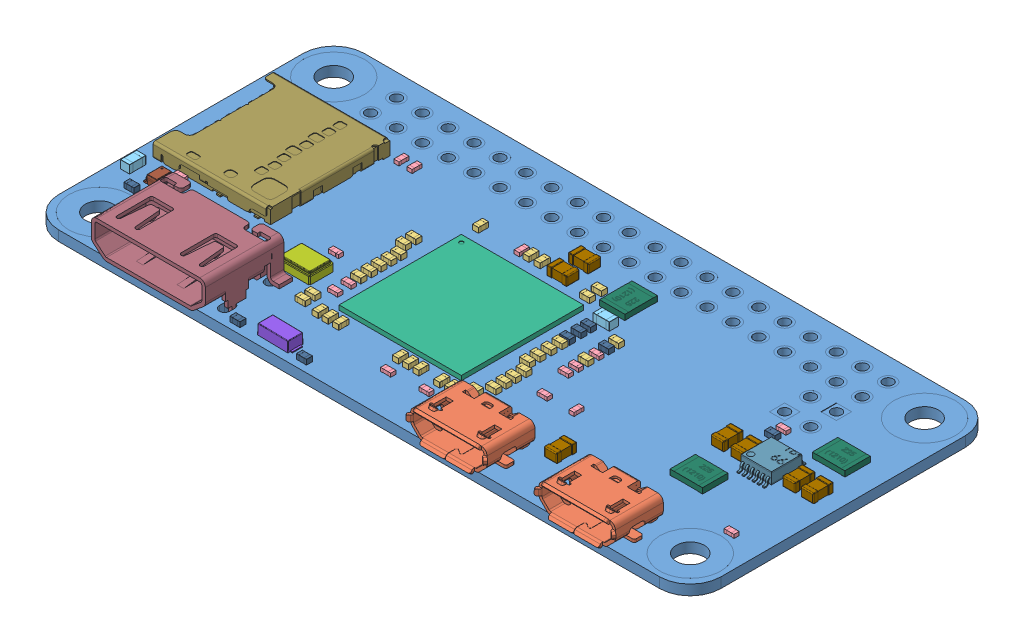
SolidWorks assembly RapberryPiZero, configuration Default. Lengths in mm.
Overall size (65 4.45 30.6).
81 component instances, 15 part files, 174 mates.
Components (placement in the parent):
- Raspberry_pizero_PCB-1: Raspberry_pizero_PCB [Default] at (-51.2564 20.0966 13.0542) size (65 1 30)
- Micro USB_input_female (short)-SMT-1: Micro USB_input_female (short)-SMT [Default] at (-42.3564 22.3216 25.8042) size (7.98 2.94 5.43)
- Micro USB_input_female (short)-SMT-2: Micro USB_input_female (short)-SMT [Default] at (-29.7564 22.3216 25.8042) size (7.98 2.94 5.43)
- 0204 - Capacitor-1: 0204 - Capacitor [Default] at (-62.4121 21.3466 11.2398) size (1 0.5 0.6)
- 0204 - Capacitor-2: 0204 - Capacitor [Default] at (-62.4121 21.3466 12.2528) size (1 0.5 0.6)
- 0204 - Capacitor-3: 0204 - Capacitor [Default] at (-61.8122 21.3466 13.3136) size (1 0.5 0.6)
- 0204 - Capacitor-4: 0204 - Capacitor [Default] at (-61.8122 21.3466 14.2646) size (1 0.5 0.6)
- 0204 - Capacitor-5: 0204 - Capacitor [Default] at (-61.8122 21.3466 15.241) size (1 0.5 0.6)
- 0204 - Capacitor-6: 0204 - Capacitor [Default] at (-61.8122 21.3466 16.2144) size (1 0.5 0.6)
- 0204 - Capacitor-7: 0204 - Capacitor [Default] at (-61.8122 21.3466 17.2416) size (1 0.5 0.6)
- 0204 - Capacitor-8: 0204 - Capacitor [Default] at (-62.5919 21.3466 20.9695) size (1 0.5 0.6)
- 0204 - Capacitor-9: 0204 - Capacitor [Default] at (-62.5919 21.3466 21.919) size (1 0.5 0.6)
- 0204 - Capacitor-10: 0204 - Capacitor [Default] at (-60.4584 21.3466 22.3712) x (0 0 1) z (-1 0 0) size (1 0.5 0.6)
- 0204 - Capacitor-11: 0204 - Capacitor [Default] at (-60.0807 21.3466 22.3712) x (0 0 -1) z (1 0 0) size (1 0.5 0.6)
- 0204 - Capacitor-12: 0204 - Capacitor [Default] at (-59.0466 21.3466 22.3712) x (0 0 -1) z (1 0 0) size (1 0.5 0.6)
- 0204 - Capacitor-13: 0204 - Capacitor [Default] at (-52.6496 21.3466 22.316) x (0 0 1) z (-1 0 0) size (1 0.5 0.6)
- 0204 - Capacitor-14: 0204 - Capacitor [Default] at (-52.25 21.3466 22.316) x (0 0 -1) z (1 0 0) size (1 0.5 0.6)
- 0204 - Capacitor-15: 0204 - Capacitor [Default] at (-51.2398 21.3466 22.316) x (0 0 -1) z (1 0 0) size (1 0.5 0.6)
- 0204 - Capacitor-16: 0204 - Capacitor [Default] at (-49.1841 21.3466 22.316) x (0 0 -1) z (1 0 0) size (1 0.5 0.6)
- 0204 - Capacitor-17: 0204 - Capacitor [Default] at (-48.1448 21.3466 22.316) x (0 0 -1) z (1 0 0) size (1 0.5 0.6)
- 0204 - Capacitor-18: 0204 - Capacitor [Default] at (-46.475 21.3466 21.113) size (1 0.5 0.6)
- 0204 - Capacitor-19: 0204 - Capacitor [Default] at (-45.7322 21.3466 20.0663) size (1 0.5 0.6)
- 0204 - Capacitor-20: 0204 - Capacitor [Default] at (-45.7322 21.3466 19.0675) size (1 0.5 0.6)
- 0204 - Capacitor-21: 0204 - Capacitor [Default] at (-45.7322 21.3466 18.1249) size (1 0.5 0.6)
- 0204 - Capacitor-22: 0204 - Capacitor [Default] at (-45.7322 21.3466 17.1095) size (1 0.5 0.6)
- 0204 - Capacitor-23: 0204 - Capacitor [Default] at (-46.3457 21.3466 16.1412) size (1 0.5 0.6)
- 0204 - Capacitor-24: 0204 - Capacitor [Default] at (-46.3457 21.3466 15.1229) size (1 0.5 0.6)
- 0204 - Capacitor-25: 0204 - Capacitor [Default] at (-46.3457 21.3466 14.0197) size (1 0.5 0.6)
- 0204 - Capacitor-26: 0204 - Capacitor [Default] at (-46.3457 21.3466 12.9589) size (1 0.5 0.6)
- 0204 - Capacitor-27: 0204 - Capacitor [Default] at (-43.6156 21.3466 13.1418) size (1 0.5 0.6)
- 0204 - Capacitor-28: 0204 - Capacitor [Default] at (-43.6156 21.3466 10.1424) size (1 0.5 0.6)
- 0204 - Capacitor-29: 0204 - Capacitor [Default] at (-48.9117 21.3466 7.6917) size (1 0.5 0.6)
- 0204 - Capacitor-30: 0204 - Capacitor [Default] at (-55.4926 21.3466 7.2526) x (0 0 -1) z (1 0 0) size (1 0.5 0.6)
- 0204 - Capacitor-31: 0204 - Capacitor [Default] at (-53.7932 21.3466 7.2526) x (0 0 1) z (-1 0 0) size (1 0.5 0.6)
- 0204 - Capacitor-32: 0204 - Capacitor [Default] at (-59.8477 21.3466 7.2526) x (0 0 1) z (-1 0 0) size (1 0.5 0.6)
- 0204- Resistor-15: 0204- Resistor [Default] at (-43.6109 21.4522 15.4193) x (-1 0 0) z (0 -1 0) size (0.99 0.51 0.36)
- 0204- Resistor-14: 0204- Resistor [Default] at (-43.6109 21.4522 14.4127) x (-1 0 0) z (0 -1 0) size (0.99 0.51 0.36)
- 0204- Resistor-13: 0204- Resistor [Default] at (-43.6109 21.4522 12.4047) x (-1 0 0) z (0 -1 0) size (0.99 0.51 0.36)
- 0204- Resistor-4: 0204- Resistor [Default] at (-42.6936 21.4522 18.4076) x (-1 0 0) z (0 -1 0) size (0.99 0.51 0.36)
- 0204- Resistor-5: 0204- Resistor [Default] at (-39.831 21.4522 18.1462) x (0 0 1) z (0 -1 0) size (0.99 0.51 0.36)
- 0204- Resistor-7: 0204- Resistor [Default] at (-61.8169 21.4522 19.8533) x (-1 0 0) z (0 -1 0) size (0.99 0.51 0.36)
- 0204- Resistor-8: 0204- Resistor [Default] at (-61.8169 21.4522 18.5178) x (-1 0 0) z (0 -1 0) size (0.99 0.51 0.36)
- 0204- Resistor-9: 0204- Resistor [Default] at (-79.148 21.4522 17.7279) x (-1 0 0) z (0 -1 0) size (0.99 0.51 0.36)
- 0204- Resistor-10: 0204- Resistor [Default] at (-56.0985 21.4522 7.2479) x (0 0 -1) z (0 -1 0) size (0.99 0.51 0.36)
- 0204- Resistor-11: 0204- Resistor [Default] at (-28.0827 21.4522 9.5819) x (-1 0 0) z (0 -1 0) size (0.99 0.51 0.36)
- 0204- Resistor-12: 0204- Resistor [Default] at (-21.8613 21.4522 20.9026) x (-1 0 0) z (0 -1 0) size (0.99 0.51 0.36)
- CAP-0306-1: CAP-0306 [Default] at (-45.8903 21.4966 8.7634) size (1.6 0.8 0.9)
- CAP-0306-2: CAP-0306 [Default] at (-82.0031 21.4966 19.0464) x (0 0 1) z (-1 0 0) size (1.6 0.8 0.9)
- Raspberry_pizero_BCM2835 with VC4-2: Raspberry_pizero_BCM2835 with VC4 [Default] at (-54.1608 21.5466 15.1238) x (1 0 0) z (0 0 -1) size (12 0.65 12)
- Crystal 3.4x2.4mm-1: Crystal 3.4x2.4mm [Default] at (-65.3089 21.0966 19.2633) size (3.2 1 2.4)
- 0204- Resistor-16: 0204- Resistor [Default] at (-68.4329 21.4522 5.4384) x (0 0 1) z (0 -1 0) size (0.99 0.51 0.36)
- 0204- Resistor-17: 0204- Resistor [Default] at (-69.7255 21.4522 5.4384) x (0 0 1) z (0 -1 0) size (0.99 0.51 0.36)
- 0204- Resistor-18: 0204- Resistor [Default] at (-65.0626 21.4522 16.5355) x (1 0 0) z (0 -1 0) size (0.99 0.51 0.36)
- 32,768 Khz Crystal-1: 32,768 Khz Crystal [Default] at (-60.5154 21.1428 26.5473) x (0.999848 -0.017452 0) z (0 0 1) size (3.4 1.03 1.5)
- 0805- Capacitor-1: 0805- Capacitor [Default] at (-51.9496 21.9966 5.2384) x (1 0 0) z (0 -1 0) size (2 1.25 0.9)
- 0805- Capacitor-2: 0805- Capacitor [Default] at (-51.9496 21.9966 7.3589) x (1 0 0) z (0 -1 0) size (2 1.25 0.9)
- 0805- Capacitor-3: 0805- Capacitor [Default] at (-37.009 21.9966 22.5384) x (0 0 -1) z (0 -1 0) size (2 1.25 0.9)
- 0805- Capacitor-4: 0805- Capacitor [Default] at (-29.8247 21.9966 13.3538) x (0 0 1) z (0 -1 0) size (2 1.25 0.9)
- 0805- Capacitor-5: 0805- Capacitor [Default] at (-27.9052 21.9966 13.3538) x (0 0 -1) z (0 -1 0) size (2 1.25 0.9)
- 0805- Capacitor-6: 0805- Capacitor [Default] at (-22.8003 21.9966 13.3538) x (0 0 -1) z (0 -1 0) size (2 1.25 0.9)
- 0805- Capacitor-7: 0805- Capacitor [Default] at (-20.9924 21.9966 13.3538) x (0 0 -1) z (0 -1 0) size (2 1.25 0.9)
- 0204- Resistor-19: 0204- Resistor [Default] at (-48.8769 21.4522 23.8207) x (1 0 0) z (0 -1 0) size (0.99 0.51 0.36)
- 0204- Resistor-20: 0204- Resistor [Default] at (-52.4165 21.4522 24.0419) x (1 0 0) z (0 -1 0) size (0.99 0.51 0.36)
- 0204 - Capacitor-33: 0204 - Capacitor [Default] at (-47.1199 21.3466 23.926) x (0 0 1) z (-1 0 0) size (1 0.5 0.6)
- 0204 - Capacitor Brown-34: 0204 - Capacitor Brown [Default] at (-57.5817 21.3466 26.803) size (1 0.5 0.6)
- 0204 - Capacitor Brown-35: 0204 - Capacitor Brown [Default] at (-64.0312 21.3466 26.8794) size (1 0.5 0.6)
- 0204 - Capacitor Brown-36: 0204 - Capacitor Brown [Default] at (-46.3457 21.3466 12.214) size (1 0.5 0.6)
- 0204 - Capacitor Brown-37: 0204 - Capacitor Brown [Default] at (-46.3457 21.3466 11.0963) size (1 0.5 0.6)
- 0204 - Capacitor Brown-38: 0204 - Capacitor Brown [Default] at (-46.3457 21.3466 10.1566) size (1 0.5 0.6)
- 0204 - Capacitor Brown-39: 0204 - Capacitor Brown [Default] at (-43.6156 21.3466 11.1151) size (1 0.5 0.6)
- 0204 - Capacitor Brown-40: 0204 - Capacitor Brown [Default] at (-28.0874 21.3466 10.3236) size (1 0.5 0.6)
- 0204 - Capacitor Brown-41: 0204 - Capacitor Brown [Default] at (-80.6197 21.3466 20.6997) size (1 0.5 0.6)
- 0204- Resistor-21: 0204- Resistor [Default] at (-78.9105 21.4522 21.1554) x (1 0 0) z (0 -1 0) size (0.99 0.51 0.36)
- 6-Pin SOT-1: 6-Pin SOT [Default] at (-79.714 21.0966 19.2138) x (0 0 1) z (0 1 0) size (1.5 1.84 0.95)
- micro sd molex-1: micro sd molex [Default] at (-74.7768 21.6766 -33.0961) x (0 0 1) z (0 1 0) size (11.95 11.4 1.45)
- hdmi type C-1: hdmi type C [Default] at (-71.3564 22.9466 28.6542) size (12.9 4.05 7.7)
- Voltage Regulator 3x3mm 12-Pin-1: Voltage Regulator 3x3mm 12-Pin [Default] at (-23.6842 21.0966 12.6105) x (1 0 0) z (0 1 0) size (3 4.1 1.2)
- 1210 inductor-1: 1210 inductor [Default] at (-46.4963 21.0916 6.3909) x (0 0 1) z (0 1 0) size (3.26 2.86 0.75)
- 1210 inductor-2: 1210 inductor [Default] at (-22.7405 21.0916 9.2394) x (1 0 0) z (0 1 0) size (3.26 2.86 0.75)
- 1210 inductor-3: 1210 inductor [Default] at (-28.2854 21.0916 17.6682) x (1 0 0) z (0 1 0) size (3.26 2.86 0.75)
- 0204 - Capacitor-34: 0204 - Capacitor [Default] at (-48.9117 21.3466 6.5273) size (1 0.5 0.6)
Mates (geometry in assembly coordinates):
- Coincident1: coincident anti-aligned: plane of Raspberry_pizero_PCB-1 through (-80.7564 21.0966 1.0542) normal (0 1 0); plane of Micro USB_input_female (short)-SMT-1 through (-46.4124 21.0966 24.1966) normal (0 -1 0)
- Coincident2: coincident anti-aligned: plane of Raspberry_pizero_PCB-1 through (-80.7564 21.0966 1.0542) normal (0 1 0); plane of Micro USB_input_female (short)-SMT-2 through (-33.8124 21.0966 24.1966) normal (0 -1 0)
- Coincident3: coincident aligned: plane of 0204 - Capacitor-13 through (-52.9516 21.5916 22.316) normal (0 1 0); plane of 0204 - Capacitor-14 through (-51.948 21.5916 22.316) normal (0 1 0)
- Coincident4: coincident aligned: plane of 0204 - Capacitor-14 through (-51.948 21.5916 22.316) normal (0 1 0); plane of 0204 - Capacitor-15 through (-50.9378 21.5916 22.316) normal (0 1 0)
- Coincident5: coincident aligned: plane of 0204 - Capacitor-15 through (-50.9378 21.5916 22.316) normal (0 1 0); plane of 0204 - Capacitor-16 through (-48.8821 21.5916 22.316) normal (0 1 0)
- Coincident6: coincident aligned: plane of 0204 - Capacitor-16 through (-48.8821 21.5916 22.316) normal (0 1 0); plane of 0204 - Capacitor-17 through (-47.8428 21.5916 22.316) normal (0 1 0)
- Coincident7: coincident aligned: plane of 0204 - Capacitor-17 through (-47.8428 21.5916 22.316) normal (0 1 0); plane of 0204 - Capacitor-18 through (-46.475 21.5916 21.415) normal (0 1 0)
- Coincident8: coincident aligned: plane of 0204 - Capacitor-18 through (-46.475 21.5916 21.415) normal (0 1 0); plane of 0204 - Capacitor-19 through (-45.7322 21.5916 20.3683) normal (0 1 0)
- Coincident9: coincident aligned: plane of 0204 - Capacitor-19 through (-45.7322 21.5916 20.3683) normal (0 1 0); plane of 0204 - Capacitor-20 through (-45.7322 21.5916 19.3695) normal (0 1 0)
- Coincident10: coincident aligned: plane of 0204 - Capacitor-20 through (-45.7322 21.5916 19.3695) normal (0 1 0); plane of 0204 - Capacitor-21 through (-45.7322 21.5916 18.4269) normal (0 1 0)
- Coincident11: coincident aligned: plane of 0204 - Capacitor-21 through (-45.7322 21.5916 18.4269) normal (0 1 0); plane of 0204 - Capacitor-22 through (-45.7322 21.5916 17.4115) normal (0 1 0)
- Coincident12: coincident aligned: plane of 0204 - Capacitor-22 through (-45.7322 21.5916 17.4115) normal (0 1 0); plane of 0204 - Capacitor-23 through (-46.3457 21.5916 16.4432) normal (0 1 0)
- Coincident13: coincident aligned: plane of 0204 - Capacitor-23 through (-46.3457 21.5916 16.4432) normal (0 1 0); plane of 0204 - Capacitor-24 through (-46.3457 21.5916 15.4249) normal (0 1 0)
- Coincident14: coincident aligned: plane of 0204 - Capacitor-24 through (-46.3457 21.5916 15.4249) normal (0 1 0); plane of 0204 - Capacitor-25 through (-46.3457 21.5916 14.3217) normal (0 1 0)
- Coincident15: coincident aligned: plane of 0204 - Capacitor-25 through (-46.3457 21.5916 14.3217) normal (0 1 0); plane of 0204 - Capacitor-26 through (-46.3457 21.5916 13.2609) normal (0 1 0)
- Coincident16: coincident aligned: plane of 0204 - Capacitor-26 through (-46.3457 21.5916 13.2609) normal (0 1 0); plane of 0204 - Capacitor-27 through (-43.6156 21.5916 13.4438) normal (0 1 0)
- Coincident17: coincident aligned: plane of 0204 - Capacitor-27 through (-43.6156 21.5916 13.4438) normal (0 1 0); plane of 0204 - Capacitor-28 through (-43.6156 21.5916 10.4444) normal (0 1 0)
- Coincident18: coincident aligned: plane of 0204 - Capacitor-28 through (-43.6156 21.5916 10.4444) normal (0 1 0); plane of 0204 - Capacitor-29 through (-48.9117 21.5916 7.9937) normal (0 1 0)
- Coincident19: coincident aligned: plane of 0204 - Capacitor-29 through (-48.9117 21.5916 7.9937) normal (0 1 0); plane of 0204 - Capacitor-31 through (-54.0952 21.5916 7.2526) normal (0 1 0)
- Coincident20: coincident aligned: plane of 0204 - Capacitor-30 through (-55.1906 21.5916 7.2526) normal (0 1 0); plane of 0204 - Capacitor-31 through (-54.0952 21.5916 7.2526) normal (0 1 0)
- Coincident21: coincident aligned: plane of 0204 - Capacitor-30 through (-55.1906 21.5916 7.2526) normal (0 1 0); plane of 0204 - Capacitor-32 through (-60.1497 21.5916 7.2526) normal (0 1 0)
- Coincident22: coincident aligned: plane of 0204 - Capacitor-1 through (-62.4121 21.5916 11.5418) normal (0 1 0); plane of 0204 - Capacitor-32 through (-60.1497 21.5916 7.2526) normal (0 1 0)
- Coincident23: coincident aligned: plane of 0204 - Capacitor-1 through (-62.4121 21.5916 11.5418) normal (0 1 0); plane of 0204 - Capacitor-2 through (-62.4121 21.5916 12.5548) normal (0 1 0)
- Coincident24: coincident aligned: plane of 0204 - Capacitor-2 through (-62.4121 21.5916 12.5548) normal (0 1 0); plane of 0204 - Capacitor-3 through (-61.8122 21.5916 13.6156) normal (0 1 0)
- Coincident25: coincident aligned: plane of 0204 - Capacitor-3 through (-61.8122 21.5916 13.6156) normal (0 1 0); plane of 0204 - Capacitor-4 through (-61.8122 21.5916 14.5666) normal (0 1 0)
- Coincident26: coincident aligned: plane of 0204 - Capacitor-4 through (-61.8122 21.5916 14.5666) normal (0 1 0); plane of 0204 - Capacitor-5 through (-61.8122 21.5916 15.543) normal (0 1 0)
- Coincident27: coincident aligned: plane of 0204 - Capacitor-5 through (-61.8122 21.5916 15.543) normal (0 1 0); plane of 0204 - Capacitor-6 through (-61.8122 21.5916 16.5164) normal (0 1 0)
- Coincident28: coincident aligned: plane of 0204 - Capacitor-6 through (-61.8122 21.5916 16.5164) normal (0 1 0); plane of 0204 - Capacitor-7 through (-61.8122 21.5916 17.5436) normal (0 1 0)
- Coincident29: coincident aligned: plane of 0204 - Capacitor-7 through (-61.8122 21.5916 17.5436) normal (0 1 0); plane of 0204 - Capacitor-8 through (-62.5919 21.5916 21.2715) normal (0 1 0)
- Coincident30: coincident aligned: plane of 0204 - Capacitor-8 through (-62.5919 21.5916 21.2715) normal (0 1 0); plane of 0204 - Capacitor-9 through (-62.5919 21.5916 22.221) normal (0 1 0)
- Coincident31: coincident aligned: plane of 0204 - Capacitor-9 through (-62.5919 21.5916 22.221) normal (0 1 0); plane of 0204 - Capacitor-10 through (-60.7604 21.5916 22.3712) normal (0 1 0)
- Coincident32: coincident aligned: plane of 0204 - Capacitor-10 through (-60.7604 21.5916 22.3712) normal (0 1 0); plane of 0204 - Capacitor-11 through (-59.7787 21.5916 22.3712) normal (0 1 0)
- Coincident33: coincident aligned: plane of 0204 - Capacitor-11 through (-59.7787 21.5916 22.3712) normal (0 1 0); plane of 0204 - Capacitor-12 through (-58.7446 21.5916 22.3712) normal (0 1 0)
- Coincident34: coincident anti-aligned: plane of Raspberry_pizero_PCB-1 through (-80.7564 21.0966 1.0542) normal (0 1 0); plane of 0204 - Capacitor-9 through (-62.9669 21.0966 22.219) normal (0 -1 0)
- Coincident35: coincident aligned: plane of 0204 - Capacitor-25 through (-46.8457 21.0966 14.3197) normal (-1 0 0); plane of 0204 - Capacitor-26 through (-46.8457 21.0966 13.2589) normal (-1 0 0)
- Coincident36: coincident aligned: plane of 0204 - Capacitor-24 through (-46.8457 21.0966 15.4229) normal (-1 0 0); plane of 0204 - Capacitor-25 through (-46.8457 21.0966 14.3197) normal (-1 0 0)
- Coincident37: coincident aligned: plane of 0204 - Capacitor-23 through (-46.8457 21.0966 16.4412) normal (-1 0 0); plane of 0204 - Capacitor-24 through (-46.8457 21.0966 15.4229) normal (-1 0 0)
- Coincident38: coincident aligned: plane of 0204 - Capacitor-27 through (-44.1156 21.0966 13.4418) normal (-1 0 0); plane of 0204 - Capacitor-28 through (-44.1156 21.0966 10.4424) normal (-1 0 0)
- Parallel1: parallel anti-aligned: plane of Raspberry_pizero_PCB-1 through (-80.7564 21.0966 -1.9458) normal (0 0 -1); plane of 0204 - Capacitor-30 through (-55.1926 21.0966 7.7526) normal (0 0 1)
- Coincident39: coincident aligned: plane of 0204 - Capacitor-30 through (-55.1926 21.0966 6.7526) normal (0 0 -1); plane of 0204 - Capacitor-31 through (-54.0932 21.0966 6.7526) normal (0 0 -1)
- Coincident40: coincident aligned: plane of 0204 - Capacitor-30 through (-55.1926 21.0966 6.7526) normal (0 0 -1); plane of 0204 - Capacitor-32 through (-60.1477 21.0966 6.7526) normal (0 0 -1)
- Coincident41: coincident aligned: plane of 0204 - Capacitor-1 through (-62.9121 21.0966 11.5398) normal (-1 0 0); plane of 0204 - Capacitor-2 through (-62.9121 21.0966 12.5528) normal (-1 0 0)
- Coincident42: coincident aligned: plane of 0204 - Capacitor-3 through (-62.3122 21.0966 13.6136) normal (-1 0 0); plane of 0204 - Capacitor-4 through (-62.3122 21.0966 14.5646) normal (-1 0 0)
- Coincident43: coincident aligned: plane of 0204 - Capacitor-4 through (-62.3122 21.0966 14.5646) normal (-1 0 0); plane of 0204 - Capacitor-5 through (-62.3122 21.0966 15.541) normal (-1 0 0)
- Coincident44: coincident aligned: plane of 0204 - Capacitor-5 through (-62.3122 21.0966 15.541) normal (-1 0 0); plane of 0204 - Capacitor-6 through (-62.3122 21.0966 16.5144) normal (-1 0 0)
- Coincident45: coincident aligned: plane of 0204 - Capacitor-6 through (-62.3122 21.0966 16.5144) normal (-1 0 0); plane of 0204 - Capacitor-7 through (-62.3122 21.0966 17.5416) normal (-1 0 0)
- Coincident46: coincident aligned: plane of 0204 - Capacitor-8 through (-63.0919 21.0966 21.2695) normal (-1 0 0); plane of 0204 - Capacitor-9 through (-63.0919 21.0966 22.219) normal (-1 0 0)
- Parallel2: parallel anti-aligned: plane of Raspberry_pizero_PCB-1 through (-80.7564 21.0966 28.0542) normal (0 0 1); plane of 0204 - Capacitor-10 through (-60.7584 21.0966 21.8712) normal (0 0 -1)
- Coincident48: coincident aligned: plane of 0204 - Capacitor-10 through (-60.7584 21.0966 22.8712) normal (0 0 1); plane of 0204 - Capacitor-11 through (-59.7807 21.0966 22.8712) normal (0 0 1)
- Coincident49: coincident aligned: plane of 0204 - Capacitor-11 through (-59.7807 21.0966 22.8712) normal (0 0 1); plane of 0204 - Capacitor-12 through (-58.7466 21.0966 22.8712) normal (0 0 1)
- Parallel3: parallel anti-aligned: plane of Raspberry_pizero_PCB-1 through (-80.7564 21.0966 28.0542) normal (0 0 1); plane of 0204 - Capacitor-13 through (-52.9496 21.0966 21.816) normal (0 0 -1)
- Coincident51: coincident aligned: plane of 0204 - Capacitor-13 through (-52.9496 21.0966 22.816) normal (0 0 1); plane of 0204 - Capacitor-14 through (-51.95 21.0966 22.816) normal (0 0 1)
- Coincident52: coincident aligned: plane of 0204 - Capacitor-14 through (-51.95 21.0966 22.816) normal (0 0 1); plane of 0204 - Capacitor-15 through (-50.9398 21.0966 22.816) normal (0 0 1)
- Coincident53: coincident aligned: plane of 0204 - Capacitor-15 through (-50.9398 21.0966 22.816) normal (0 0 1); plane of 0204 - Capacitor-16 through (-48.8841 21.0966 22.816) normal (0 0 1)
- Coincident54: coincident aligned: plane of 0204 - Capacitor-16 through (-48.8841 21.0966 22.816) normal (0 0 1); plane of 0204 - Capacitor-17 through (-47.8448 21.0966 22.816) normal (0 0 1)
- Coincident55: coincident anti-aligned: plane of Raspberry_pizero_PCB-1 through (-80.7564 21.0966 1.0542) normal (0 1 0); plane of ? through (-81.0969 21.0966 20.6546) normal (0 -1 0)
- Coincident56: coincident aligned: plane of ? through (-61.5587 21.4548 20.0688) normal (0 1 0); plane of ? through (-80.3095 21.4548 21.1576) normal (0 1 0)
- Coincident57: coincident aligned: plane of ? through (-61.5587 21.4548 20.0688) normal (0 1 0); plane of ? through (-61.5587 21.4548 18.7577) normal (0 1 0)
- Coincident58: coincident aligned: plane of ? through (-61.5587 21.4548 18.7577) normal (0 1 0); plane of ? through (-57.9681 21.4548 7.011) normal (0 1 0)
- Coincident59: coincident aligned: plane of ? through (-43.2341 21.4548 12.6019) normal (0 1 0); plane of ? through (-57.9681 21.4548 7.011) normal (0 1 0)
- Coincident60: coincident aligned: plane of ? through (-43.2341 21.4548 14.6137) normal (0 1 0); plane of ? through (-43.2341 21.4548 12.6019) normal (0 1 0)
- Coincident61: coincident aligned: plane of ? through (-43.2341 21.4548 15.6074) normal (0 1 0); plane of ? through (-43.2341 21.4548 14.6137) normal (0 1 0)
- Coincident62: coincident aligned: plane of ? through (-43.2341 21.4548 15.6074) normal (0 1 0); plane of ? through (-42.4793 21.4548 18.6674) normal (0 1 0)
- Coincident63: coincident aligned: plane of ? through (-42.4793 21.4548 18.6674) normal (0 1 0); plane of ? through (-40.0544 21.4548 18.4625) normal (0 1 0)
- Coincident65: coincident anti-aligned: plane of ? through (-27.5651 21.0966 9.2269) normal (0 -1 0); plane of Raspberry_pizero_PCB-1 through (-80.7564 21.0966 1.0542) normal (0 1 0)
- Coincident66: coincident aligned: plane of ? through (-27.7683 21.4548 9.7299) normal (0 1 0); plane of ? through (-21.604 21.4548 21.0312) normal (0 1 0)
- Coincident67: coincident aligned: plane of 0204 - Capacitor-7 through (-62.3461 21.0966 17.5416) normal (-1 0 0); plane of ? through (-62.3461 21.4522 18.2547) normal (-1 0 0)
- Coincident68: coincident aligned: plane of ? through (-62.3461 21.4522 19.5658) normal (-1 0 0); plane of ? through (-62.3461 21.4522 18.2547) normal (-1 0 0)
- Coincident69: coincident aligned: plane of 0204 - Capacitor-30 through (-55.7773 21.0966 6.2236) normal (0 0 -1); plane of ? through (-57.4651 21.4522 6.2236) normal (0 0 -1)
- Coincident70: coincident aligned: plane of 0204 - Capacitor-28 through (-44.0215 21.0966 10.4424) normal (-1 0 0); plane of ? through (-44.0215 21.4522 12.0989) normal (-1 0 0)
- Coincident71: coincident aligned: plane of 0204 - Capacitor-27 through (-44.0215 21.0966 13.4418) normal (-1 0 0); plane of ? through (-44.0215 21.4522 14.1107) normal (-1 0 0)
- Coincident72: coincident aligned: plane of ? through (-44.0215 21.4522 15.1044) normal (-1 0 0); plane of ? through (-44.0215 21.4522 14.1107) normal (-1 0 0)
- Parallel4: parallel anti-aligned: plane of Raspberry_pizero_PCB-1 through (-80.7564 21.0966 28.0542) normal (0 0 1); plane of ? through (-39.5514 21.4522 17.6751) normal (0 0 -1)
- Parallel5: parallel aligned: plane of Raspberry_pizero_PCB-1 through (-18.7564 21.0966 25.0542) normal (1 0 0); plane of ? through (-21.4008 21.4522 20.5282) normal (1 0 0)
- Parallel6: parallel aligned: plane of Raspberry_pizero_PCB-1 through (-18.7564 21.0966 25.0542) normal (1 0 0); plane of ? through (-27.5651 21.4522 9.2269) normal (1 0 0)
- Parallel7: parallel anti-aligned: plane of Raspberry_pizero_PCB-1 through (-80.7564 21.0966 28.0542) normal (0 0 1); plane of CAP-0306-2 through (-82.4531 21.0966 18.2464) normal (0 0 -1)
- Parallel8: parallel aligned: plane of Raspberry_pizero_PCB-1 through (-18.7564 21.0966 25.0542) normal (1 0 0); plane of CAP-0306-1 through (-45.0903 21.0966 9.2134) normal (1 0 0)
- Coincident77: coincident aligned: plane of 0204 - Capacitor-21 through (-46.2322 21.0966 18.4249) normal (-1 0 0); plane of 0204 - Capacitor-22 through (-46.2322 21.0966 17.4095) normal (-1 0 0)
- Coincident78: coincident aligned: plane of 0204 - Capacitor-20 through (-46.2322 21.0966 19.3675) normal (-1 0 0); plane of 0204 - Capacitor-21 through (-46.2322 21.0966 18.4249) normal (-1 0 0)
- Coincident79: coincident aligned: plane of 0204 - Capacitor-19 through (-46.2322 21.0966 20.3663) normal (-1 0 0); plane of 0204 - Capacitor-20 through (-46.2322 21.0966 19.3675) normal (-1 0 0)
- Coincident80: coincident aligned: plane of Micro USB_input_female (short)-SMT-1 through (-39.2364 21.3596 23.1542) normal (0 0 -1); plane of Micro USB_input_female (short)-SMT-2 through (-26.6364 21.3596 23.1542) normal (0 0 -1)
- Distance1: distance = 41.4 mm: moEndPointRef_w of Micro USB_input_female (short)-SMT-1; plane of Raspberry_pizero_PCB-1 through (-83.7564 21.0966 25.0542) normal (-1 0 0)
- Distance3: distance = 0.1 mm aligned: plane of Micro USB_input_female (short)-SMT-1 through (-46.2564 21.0476 28.1542) normal (0 0 1); plane of Raspberry_pizero_PCB-1 through (-80.7564 21.0966 28.0542) normal (0 0 1)
- Distance4: distance = 54 mm: moEndPointRef_w of Micro USB_input_female (short)-SMT-2; plane of Raspberry_pizero_PCB-1 through (-83.7564 21.0966 25.0542) normal (-1 0 0)
- Coincident86: coincident anti-aligned: plane of Raspberry_pizero_PCB-1 through (-80.7564 21.0966 1.0542) normal (0 1 0); plane of Raspberry_pizero_BCM2835 with VC4-2 through (-54.1608 21.0966 15.1238) normal (0 -1 0)
- Parallel10: parallel anti-aligned: plane of Raspberry_pizero_BCM2835 with VC4-2 through (-60.1608 21.0966 9.1238) normal (0 0 -1); plane of Raspberry_pizero_PCB-1 through (-80.7564 21.0966 28.0542) normal (0 0 1)
- Coincident88: coincident anti-aligned: plane of Raspberry_pizero_PCB-1 through (-80.7564 21.0966 1.0542) normal (0 1 0); plane of CAP-0306-1 through (-45.2653 21.0966 9.2134) normal (0 -1 0)
- Coincident89: coincident aligned: plane of 0204- Resistor-7 through (-61.5248 21.0966 19.5993) normal (0 -1 0); plane of 0204- Resistor-8 through (-61.5248 21.0966 18.2638) normal (0 -1 0)
- Coincident90: coincident anti-aligned: plane of Raspberry_pizero_PCB-1 through (-80.7564 21.0966 1.0542) normal (0 1 0); plane of 0204- Resistor-8 through (-61.5248 21.0966 18.2638) normal (0 -1 0)
- Parallel11: parallel aligned: plane of Raspberry_pizero_PCB-1 through (-80.7564 21.0966 28.0542) normal (0 0 1); plane of 0204 - Capacitor-7 through (-61.8122 21.1016 17.8406) normal (0 0 1)
- Coincident92: coincident aligned: plane of 0204 - Capacitor-7 through (-62.3122 21.0966 17.5416) normal (-1 0 0); plane of 0204- Resistor-8 through (-62.3122 21.0966 18.2638) normal (-1 0 0)
- Coincident93: coincident aligned: plane of 0204- Resistor-7 through (-62.3122 21.0966 19.5993) normal (-1 0 0); plane of 0204- Resistor-8 through (-62.3122 21.0966 18.2638) normal (-1 0 0)
- Coincident94: coincident aligned: plane of 0204 - Capacitor-30 through (-55.1926 21.0966 6.7526) normal (0 0 -1); plane of 0204- Resistor-10 through (-55.8445 21.0966 6.7526) normal (0 0 -1)
- Coincident95: coincident anti-aligned: plane of Raspberry_pizero_PCB-1 through (-80.7564 21.0966 1.0542) normal (0 1 0); plane of 0204- Resistor-10 through (-55.8445 21.0966 6.9558) normal (0 -1 0)
- Coincident96: coincident aligned: plane of 0204- Resistor-14 through (-43.903 21.0966 14.1587) normal (0 -1 0); plane of 0204- Resistor-13 through (-43.903 21.0966 12.1507) normal (0 -1 0)
- Coincident97: coincident aligned: plane of 0204- Resistor-15 through (-43.903 21.0966 15.1653) normal (0 -1 0); plane of 0204- Resistor-14 through (-43.903 21.0966 14.1587) normal (0 -1 0)
- Coincident98: coincident aligned: plane of 0204- Resistor-15 through (-43.903 21.0966 15.1653) normal (0 -1 0); plane of 0204- Resistor-4 through (-42.9857 21.0966 18.1536) normal (0 -1 0)
- Coincident99: coincident anti-aligned: plane of Raspberry_pizero_PCB-1 through (-80.7564 21.0966 1.0542) normal (0 1 0); plane of 0204- Resistor-15 through (-43.903 21.0966 15.1653) normal (0 -1 0)
- Coincident101: coincident aligned: plane of 0204- Resistor-5 through (-40.085 21.0966 18.4383) normal (0 -1 0); plane of 0204- Resistor-11 through (-27.7906 21.0966 9.3279) normal (0 -1 0)
- Coincident102: coincident aligned: plane of 0204- Resistor-11 through (-27.7906 21.0966 9.3279) normal (0 -1 0); plane of 0204- Resistor-12 through (-21.5692 21.0966 20.6486) normal (0 -1 0)
- Coincident103: coincident anti-aligned: plane of Raspberry_pizero_PCB-1 through (-80.7564 21.0966 1.0542) normal (0 1 0); plane of Crystal 3.4x2.4mm-1 through (-65.3089 21.0966 19.2633) normal (0 -1 0)
- Parallel12: parallel aligned: plane of Raspberry_pizero_PCB-1 through (-80.7564 21.0966 28.0542) normal (0 0 1); plane of Crystal 3.4x2.4mm-1 through (-66.9089 21.7966 20.4633) normal (0 0 1)
- Coincident104: coincident anti-aligned: plane of Raspberry_pizero_PCB-1 through (-80.7564 21.0966 1.0542) normal (0 1 0); plane of 0204- Resistor-9 through (-78.8559 21.0966 17.4739) normal (0 -1 0)
- Parallel13: parallel aligned: plane of Raspberry_pizero_PCB-1 through (-80.7564 21.0966 28.0542) normal (0 0 1); plane of 0204- Resistor-9 through (-78.2985 21.4532 17.9829) normal (0 0 1)
- Coincident105: coincident anti-aligned: plane of Raspberry_pizero_PCB-1 through (-80.7564 21.0966 1.0542) normal (0 1 0); plane of CAP-0306-2 through (-82.4531 21.0966 19.6714) normal (0 -1 0)
- Coincident106: coincident aligned: plane of 0204 - Capacitor-28 through (-43.1156 21.0966 10.4424) normal (1 0 0); plane of 0204- Resistor-13 through (-43.1156 21.0966 12.1507) normal (1 0 0)
- Coincident107: coincident aligned: plane of 0204 - Capacitor-27 through (-43.1156 21.0966 13.4418) normal (1 0 0); plane of 0204- Resistor-14 through (-43.1156 21.0966 14.1587) normal (1 0 0)
- Parallel14: parallel aligned: plane of Raspberry_pizero_PCB-1 through (-80.7564 21.0966 28.0542) normal (0 0 1); plane of 0204- Resistor-14 through (-42.7614 21.4532 14.6677) normal (0 0 1)
- Coincident110: coincident aligned: plane of 0204- Resistor-15 through (-43.1156 21.0966 15.1653) normal (1 0 0); plane of 0204- Resistor-14 through (-43.1156 21.0966 14.1587) normal (1 0 0)
- Parallel15: parallel aligned: plane of 0204- Resistor-15 through (-43.1156 21.0966 15.1653) normal (1 0 0); plane of 0204- Resistor-4 through (-42.1983 21.0966 18.1536) normal (1 0 0)
- Parallel16: parallel aligned: plane of Raspberry_pizero_PCB-1 through (-80.7564 21.0966 28.0542) normal (0 0 1); plane of 0204- Resistor-5 through (-40.085 21.0966 18.6415) normal (0 0 1)
- Coincident112: coincident anti-aligned: plane of Raspberry_pizero_PCB-1 through (-80.7564 21.0966 1.0542) normal (0 1 0); plane of 0204- Resistor-5 through (-40.085 21.0966 18.4383) normal (0 -1 0)
- Parallel17: parallel aligned: plane of Raspberry_pizero_PCB-1 through (-18.7564 21.0966 25.0542) normal (1 0 0); plane of 0204- Resistor-12 through (-21.366 21.0966 20.6486) normal (1 0 0)
- Parallel18: parallel aligned: plane of 0204- Resistor-11 through (-27.5874 21.0966 9.3279) normal (1 0 0); plane of 0204- Resistor-12 through (-21.366 21.0966 20.6486) normal (1 0 0)
- Coincident115: coincident anti-aligned: plane of Raspberry_pizero_PCB-1 through (-80.7564 21.0966 1.0542) normal (0 1 0); plane of 0204- Resistor-16 through (-68.6869 21.0966 5.1463) normal (0 -1 0)
- Coincident116: coincident aligned: plane of 0204- Resistor-16 through (-68.6879 21.4532 4.5889) normal (0 1 0); plane of 0204- Resistor-17 through (-69.9805 21.4532 4.5889) normal (0 1 0)
- Coincident117: coincident aligned: plane of 0204- Resistor-17 through (-69.9805 21.4532 4.5889) normal (0 1 0); plane of 0204- Resistor-18 through (-65.9121 21.4532 16.7905) normal (0 1 0)
- Coincident118: coincident aligned: plane of 0204- Resistor-16 through (-68.6869 21.0966 5.9337) normal (0 0 1); plane of 0204- Resistor-17 through (-69.9795 21.0966 5.9337) normal (0 0 1)
- Parallel19: parallel anti-aligned: plane of Raspberry_pizero_PCB-1 through (-80.7564 21.0966 -1.9458) normal (0 0 -1); plane of 0204- Resistor-17 through (-69.9795 21.0966 5.9337) normal (0 0 1)
- Parallel20: parallel aligned: plane of Raspberry_pizero_PCB-1 through (-80.7564 21.0966 28.0542) normal (0 0 1); plane of 0204- Resistor-18 through (-65.9121 21.4532 16.7905) normal (0 0 1)
- Coincident120: coincident anti-aligned: plane of Raspberry_pizero_PCB-1 through (-80.7564 21.0966 1.0542) normal (0 1 0); plane of 32,768 Khz Crystal-1 through (-59.5156 21.0966 27.0473) normal (0 -1 0)
- Coincident121: coincident anti-aligned: plane of Raspberry_pizero_PCB-1 through (-80.7564 21.0966 1.0542) normal (0 1 0); plane of 0805- Capacitor-1 through (-52.9496 21.0966 5.8634) normal (0 -1 0)
- Coincident122: coincident anti-aligned: plane of Raspberry_pizero_PCB-1 through (-80.7564 21.0966 1.0542) normal (0 1 0); plane of 0805- Capacitor-2 through (-52.9496 21.0966 7.9839) normal (0 -1 0)
- Coincident123: coincident anti-aligned: plane of Raspberry_pizero_PCB-1 through (-80.7564 21.0966 1.0542) normal (0 1 0); plane of 0805- Capacitor-3 through (-37.634 21.0966 21.5384) normal (0 -1 0)
- Coincident124: coincident anti-aligned: plane of Raspberry_pizero_PCB-1 through (-80.7564 21.0966 1.0542) normal (0 1 0); plane of 0805- Capacitor-4 through (-30.4497 21.0966 12.3538) normal (0 -1 0)
- Coincident125: coincident anti-aligned: plane of Raspberry_pizero_PCB-1 through (-80.7564 21.0966 1.0542) normal (0 1 0); plane of 0805- Capacitor-5 through (-27.2802 21.0966 14.3538) normal (0 -1 0)
- Parallel21: parallel anti-aligned: plane of Raspberry_pizero_PCB-1 through (-80.7564 21.0966 28.0542) normal (0 0 1); plane of 0805- Capacitor-4 through (-29.8247 21.9966 12.3538) normal (0 0 -1)
- Coincident126: coincident aligned: plane of 0805- Capacitor-4 through (-29.8247 21.9966 14.3538) normal (0 0 1); plane of 0805- Capacitor-5 through (-27.9052 21.9966 14.3538) normal (0 0 1)
- Coincident127: coincident anti-aligned: plane of Raspberry_pizero_PCB-1 through (-80.7564 21.0966 1.0542) normal (0 1 0); plane of 0805- Capacitor-6 through (-22.1753 21.0966 14.3538) normal (0 -1 0)
- Coincident128: coincident anti-aligned: plane of Raspberry_pizero_PCB-1 through (-80.7564 21.0966 1.0542) normal (0 1 0); plane of 0805- Capacitor-7 through (-20.3674 21.0966 14.3538) normal (0 -1 0)
- Coincident129: coincident aligned: plane of 0805- Capacitor-5 through (-27.9052 21.9966 14.3538) normal (0 0 1); plane of 0805- Capacitor-6 through (-22.8003 21.9966 14.3538) normal (0 0 1)
- Coincident130: coincident aligned: plane of 0805- Capacitor-6 through (-22.8003 21.9966 14.3538) normal (0 0 1); plane of 0805- Capacitor-7 through (-20.9924 21.9966 14.3538) normal (0 0 1)
- Parallel22: parallel anti-aligned: plane of Raspberry_pizero_PCB-1 through (-80.7564 21.0966 28.0542) normal (0 0 1); plane of 0805- Capacitor-3 through (-37.009 21.9966 21.5384) normal (0 0 -1)
- Coincident131: coincident aligned: plane of 0805- Capacitor-1 through (-50.9496 21.9966 5.2384) normal (1 0 0); plane of 0805- Capacitor-2 through (-50.9496 21.9966 7.3589) normal (1 0 0)
- Parallel23: parallel anti-aligned: plane of Raspberry_pizero_PCB-1 through (-80.7564 21.0966 28.0542) normal (0 0 1); plane of 6-Pin SOT-1 through (-80.214 22.0466 18.4638) normal (0 0 -1)
- Coincident134: coincident anti-aligned: plane of Raspberry_pizero_PCB-1 through (-80.7564 21.0966 1.0542) normal (0 1 0); plane of 6-Pin SOT-1 through (-80.434 21.0966 19.8263) normal (0 -1 0)
- Coincident135: coincident anti-aligned: plane of Raspberry_pizero_PCB-1 through (-80.7564 21.0966 1.0542) normal (0 1 0); plane of micro sd molex-1 through (-71.1444 21.0966 16.7043) normal (0 -1 0)
- Parallel24: parallel aligned: plane of Raspberry_pizero_PCB-1 through (-80.7564 21.0966 -1.9458) normal (0 0 -1); plane of micro sd molex-1 through (-84.5393 22.448 5.3989) normal (0 0 -1)
- Coincident141: coincident anti-aligned: plane of Raspberry_pizero_PCB-1 through (-80.7564 21.0966 1.0542) normal (0 1 0); plane of hdmi type C-1 through (-77.8064 21.0966 20.9542) normal (0 -1 0)
- Distance5: distance = 12.4 mm: moEndPointRef_w of hdmi type C-1; plane of Raspberry_pizero_PCB-1 through (-83.7564 21.0966 25.0542) normal (-1 0 0)
- Distance6: distance = 17.2 mm: moEndPointRef_w of micro sd molex-1; plane of Raspberry_pizero_PCB-1 through (-80.7564 21.0966 28.0542) normal (0 0 1)
- Parallel25: parallel aligned: plane of Raspberry_pizero_PCB-1 through (-80.7564 21.0966 28.0542) normal (0 0 1); plane of hdmi type C-1 through (-71.3564 22.9466 28.6542) normal (0 0 1)
- Distance7: distance = 0.6 mm aligned: plane of hdmi type C-1 through (-71.3564 22.9466 28.6542) normal (0 0 1); plane of Raspberry_pizero_PCB-1 through (-80.7564 21.0966 28.0542) normal (0 0 1)
- Coincident142: coincident anti-aligned: plane of Raspberry_pizero_PCB-1 through (-80.7564 21.0966 1.0542) normal (0 1 0); plane of 0204 - Capacitor Brown-34 through (-57.9567 21.0966 27.103) normal (0 -1 0)
- Coincident143: coincident aligned: plane of 0204 - Capacitor Brown-34 through (-57.5817 21.5916 27.105) normal (0 1 0); plane of 0204 - Capacitor Brown-35 through (-64.0312 21.5916 27.1814) normal (0 1 0)
- Coincident144: coincident aligned: plane of 0204 - Capacitor-18 through (-46.475 21.5916 21.415) normal (0 1 0); plane of 0204 - Capacitor-33 through (-47.4219 21.5916 23.926) normal (0 1 0)
- Parallel26: parallel anti-aligned: plane of Raspberry_pizero_PCB-1 through (-80.7564 21.0966 28.0542) normal (0 0 1); plane of 0204 - Capacitor-33 through (-47.4199 21.0966 23.426) normal (0 0 -1)
- Coincident146: coincident anti-aligned: plane of Raspberry_pizero_PCB-1 through (-80.7564 21.0966 1.0542) normal (0 1 0); plane of 0204- Resistor-19 through (-48.5848 21.0966 24.0747) normal (0 -1 0)
- Coincident147: coincident anti-aligned: plane of Raspberry_pizero_PCB-1 through (-80.7564 21.0966 1.0542) normal (0 1 0); plane of 0204- Resistor-20 through (-52.1244 21.0966 24.2959) normal (0 -1 0)
- Coincident148: coincident anti-aligned: plane of Raspberry_pizero_PCB-1 through (-80.7564 21.0966 1.0542) normal (0 1 0); plane of 0204- Resistor-21 through (-79.2026 21.0966 21.4094) normal (0 -1 0)
- Coincident149: coincident anti-aligned: plane of Raspberry_pizero_PCB-1 through (-80.7564 21.0966 1.0542) normal (0 1 0); plane of 0204 - Capacitor Brown-41 through (-80.9947 21.0966 20.9997) normal (0 -1 0)
- Parallel27: parallel aligned: plane of Raspberry_pizero_PCB-1 through (-80.7564 21.0966 28.0542) normal (0 0 1); plane of 0204- Resistor-21 through (-78.9105 21.4522 21.4094) normal (0 0 1)
- Parallel28: parallel aligned: plane of Raspberry_pizero_PCB-1 through (-80.7564 21.0966 28.0542) normal (0 0 1); plane of 0204 - Capacitor Brown-41 through (-80.6197 21.1016 21.2987) normal (0 0 1)
- Parallel29: parallel aligned: plane of 0204- Resistor-19 through (-49.7264 21.4532 24.0757) normal (0 0 1); plane of 0204- Resistor-20 through (-53.266 21.4532 24.2969) normal (0 0 1)
- Coincident152: coincident aligned: plane of 0204 - Capacitor Brown-34 through (-57.5817 21.5916 27.105) normal (0 1 0); plane of 0204 - Capacitor Brown-39 through (-43.6156 21.5916 11.4171) normal (0 1 0)
- Coincident153: coincident aligned: plane of 0204 - Capacitor Brown-36 through (-46.3457 21.5916 12.516) normal (0 1 0); plane of 0204 - Capacitor Brown-39 through (-43.6156 21.5916 11.4171) normal (0 1 0)
- Coincident154: coincident aligned: plane of 0204 - Capacitor Brown-36 through (-46.3457 21.5916 12.516) normal (0 1 0); plane of 0204 - Capacitor Brown-37 through (-46.3457 21.5916 11.3983) normal (0 1 0)
- Coincident155: coincident aligned: plane of 0204 - Capacitor Brown-37 through (-46.3457 21.5916 11.3983) normal (0 1 0); plane of 0204 - Capacitor Brown-38 through (-46.3457 21.5916 10.4586) normal (0 1 0)
- Coincident156: coincident aligned: plane of 0204 - Capacitor-26 through (-45.8457 21.0966 13.2589) normal (1 0 0); plane of 0204 - Capacitor Brown-36 through (-45.8457 21.0966 12.514) normal (1 0 0)
- Coincident157: coincident aligned: plane of 0204 - Capacitor Brown-36 through (-45.8457 21.0966 12.514) normal (1 0 0); plane of 0204 - Capacitor Brown-37 through (-45.8457 21.0966 11.3963) normal (1 0 0)
- Coincident158: coincident aligned: plane of 0204 - Capacitor Brown-37 through (-45.8457 21.0966 11.3963) normal (1 0 0); plane of 0204 - Capacitor Brown-38 through (-45.8457 21.0966 10.4566) normal (1 0 0)
- Coincident159: coincident aligned: plane of 0204 - Capacitor-28 through (-43.1156 21.0966 10.4424) normal (1 0 0); plane of 0204 - Capacitor Brown-39 through (-43.1156 21.0966 11.4151) normal (1 0 0)
- Coincident160: coincident aligned: plane of 0204 - Capacitor Brown-39 through (-43.6156 21.5916 11.4171) normal (0 1 0); plane of 0204 - Capacitor Brown-40 through (-28.0874 21.5916 10.6256) normal (0 1 0)
- Coincident161: coincident aligned: plane of 0204- Resistor-11 through (-27.5874 21.0966 9.3279) normal (1 0 0); plane of 0204 - Capacitor Brown-40 through (-27.5874 21.0966 10.6236) normal (1 0 0)
- Coincident163: coincident anti-aligned: plane of Raspberry_pizero_PCB-1 through (-80.7564 21.0966 1.0542) normal (0 1 0); plane of Voltage Regulator 3x3mm 12-Pin-1 through (-24.1342 21.0966 11.3118) normal (0 -1 0)
- Parallel30: parallel aligned: plane of Raspberry_pizero_PCB-1 through (-18.7564 21.0966 25.0542) normal (1 0 0); plane of Voltage Regulator 3x3mm 12-Pin-1 through (-23.9842 22.2966 11.8605) normal (1 0 0)
- Coincident165: coincident anti-aligned: plane of Raspberry_pizero_PCB-1 through (-80.7564 21.0966 1.0542) normal (0 1 0); line of 1210 inductor-2 through (-21.1405 21.0966 7.9944) axis (0 0 1)
- Coincident166: coincident aligned: plane of 1210 inductor-3 through (-28.2854 21.6416 16.4182) normal (0 1 0); plane of 1210 inductor-2 through (-22.7405 21.6416 7.9894) normal (0 1 0)
- Coincident167: coincident aligned: plane of 0204 - Capacitor-29 through (-48.9117 21.5916 7.9937) normal (0 1 0); plane of 0204 - Capacitor-34 through (-48.9117 21.5916 6.8293) normal (0 1 0)
- Coincident168: coincident aligned: plane of 0204 - Capacitor-29 through (-49.4117 21.0966 7.9917) normal (-1 0 0); plane of 0204 - Capacitor-34 through (-49.4117 21.0966 6.8273) normal (-1 0 0)
- Coincident169: coincident aligned: plane of 1210 inductor-1 through (-45.2463 21.6416 6.3909) normal (0 1 0); plane of 1210 inductor-2 through (-22.7405 21.6416 7.9894) normal (0 1 0)
- Parallel31: parallel aligned: plane of Raspberry_pizero_PCB-1 through (-18.7564 21.0966 25.0542) normal (1 0 0); plane of 1210 inductor-2 through (-21.1405 21.3666 10.4894) normal (1 0 0)
- Parallel32: parallel aligned: plane of Raspberry_pizero_PCB-1 through (-18.7564 21.0966 25.0542) normal (1 0 0); plane of 1210 inductor-3 through (-26.6854 21.3666 18.9182) normal (1 0 0)
- Parallel33: parallel aligned: plane of Raspberry_pizero_PCB-1 through (-18.7564 21.0966 25.0542) normal (1 0 0); plane of 1210 inductor-1 through (-45.2468 21.3666 6.3909) normal (1 0 0)
